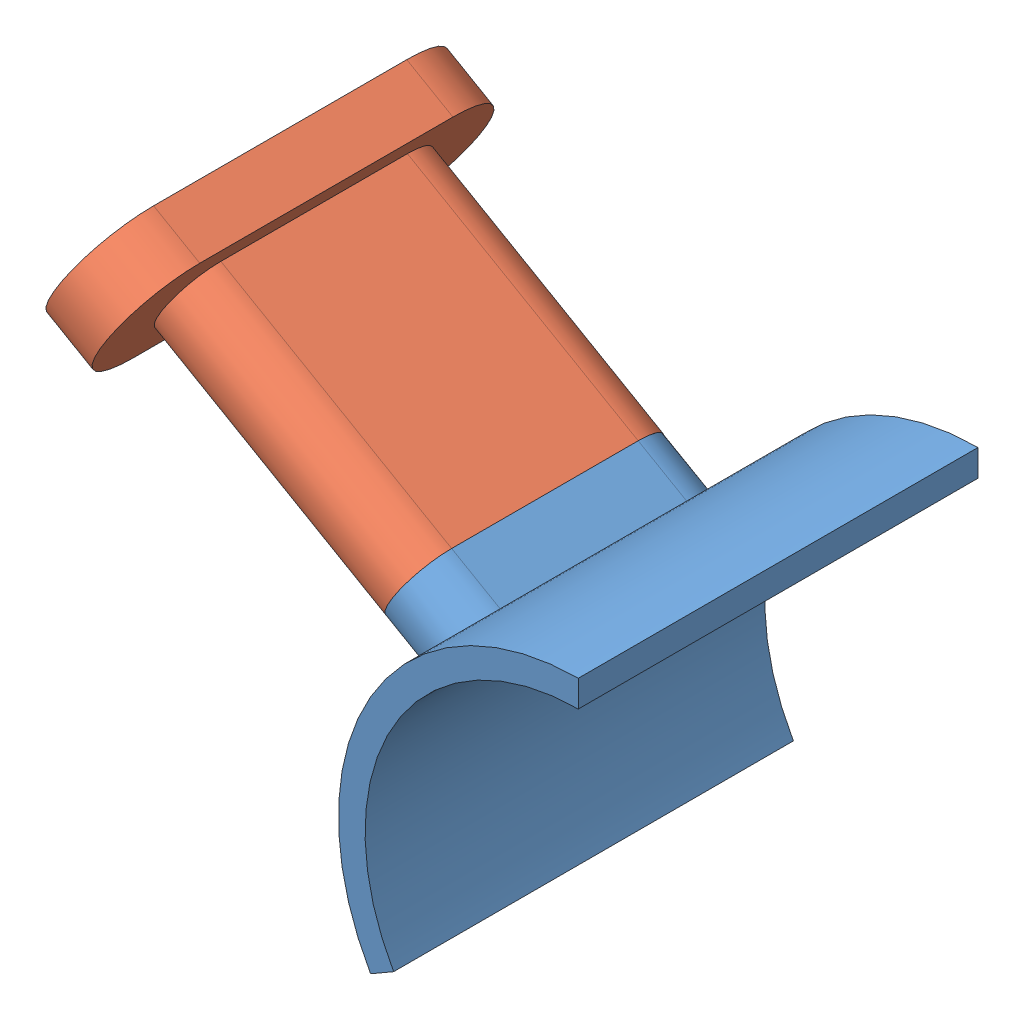
SolidWorks assembly morts à ressort, configuration Défaut. Lengths in mm.
Overall size (21.19 18.14 15).
2 component instances, 2 part files, 3 mates.
Components (placement in the parent):
- Pièce1-1: Pièce1 [Défaut] at origin size (16.7 15.75 15)
- Mort 2-1: Mort 2 [Défaut] at (-18.203 10.4715 0.0177) x (0.5 0.866025 0) z (-0.866025 0.5 0) size (5 14.5 12)
Mates (geometry in assembly coordinates):
- Coaxiale1: concentric aligned: circle of Pièce1-1; circle of Mort 2-1
- Coaxiale2: concentric aligned: circle of Pièce1-1; circle of Mort 2-1
- Coïncidente7: coincident anti-aligned: plane of Pièce1-1 through (-9.5263 5.5 -4) normal (-0.866025 0.5 0); plane of Mort 2-1 through (-9.5263 5.5 -11) normal (0.866025 -0.5 0)
